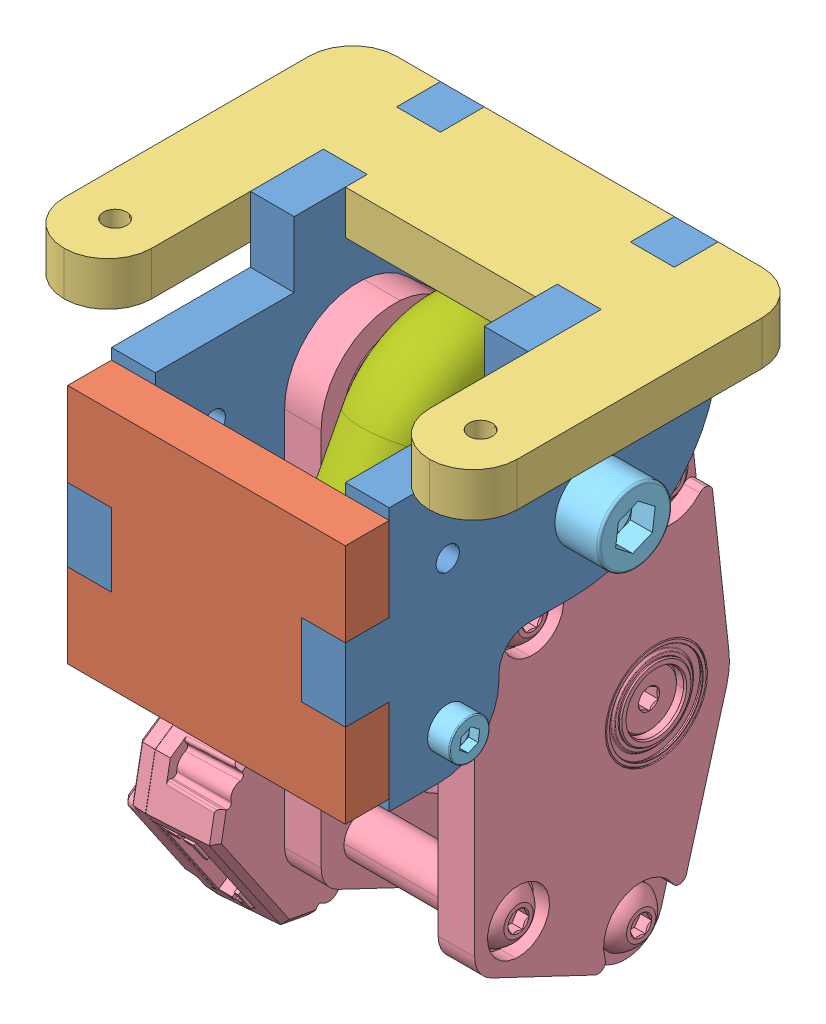
SolidWorks assembly Suporte odometria horizontal, configuration Valor predeterminado. Lengths in mm.
Overall size (62 88.3 69.49).
10 component instances, 7 part files, 21 mates.
Components (placement in the parent):
- M04.03.05.Lateral horizontal-1: M04.03.05.Lateral horizontal [Valor predeterminado] at (-73.7774 27.1656 115.2124) x (0 -1 0) z (-1 0 0) size (45 51 6)
- M04.03.06.Superior 6-1: M04.03.06.Superior 6 [Valor predeterminado] at (-60.7774 0.1656 115.2124) x (0 -1 0) z (0 0 1) size (33 38 6)
- M04.03.05.Lateral horizontal-2: M04.03.05.Lateral horizontal [Valor predeterminado] at (-41.7774 27.1656 115.2124) x (0 -1 0) z (-1 0 0) size (45 51 6)
- M04.03.07.Inferior 6-3: M04.03.07.Inferior 6 [Valor predeterminado] at (-60.7774 21.1656 79.7124) x (0 0 1) z (0 1 0) size (45.5 62 6)
- M04.03.08.Odometria-2: M04.03.08.Odometria [Valor predeterminado] at (-67.1156 -18.3079 73.5422) x (0 -0.996661 0.081653) z (1 0 0) size (73.49 51.17 39.86)
- socket head cap screw_iso-8: socket head cap screw_iso [ISO 4762 M6 x 10 - 10N] at (-35.7774 5.0156 87.5315) x (-1 0 0) z (0 0.924225 0.381849) size (16 10 10)
- torque nut 08_iso-1: torque nut 08_iso [ISO 10511-M3-N] at (-81.3274 11.0156 87.5315) x (0 0 1) z (-1 0 0) size (5.5 6.35 3.9)
- M04.03.09.Mola-1: M04.03.09.Mola [Valor predeterminado] at (-59.2813 4.7533 87.3426) x (0 -0.980257 0.197728) z (-1 0 0) size (38.69 42.17 12)
- socket head cap screw_iso-9: socket head cap screw_iso [ISO 4762 M3 x 40 - 40N] at (-38.7774 -11.8344 107.2124) x (-1 0 0) z (0 0.924225 0.381849) size (43 5.5 5.5)
- torque nut 08_iso-2: torque nut 08_iso [ISO 10511-M3-N] at (-81.3274 -11.8344 107.2124) x (0 0 1) z (-1 0 0) size (5.5 6.35 3.9)
Mates (geometry in assembly coordinates):
- Coincidente4: coincident anti-aligned: plane of M04.03.05.Lateral horizontal-1 through (-73.7774 27.1656 115.2124) normal (1 0 0); plane of M04.03.06.Superior 6-1 through (-73.7774 0.1656 121.2124) normal (-1 0 0)
- Coincidente5: coincident aligned: plane of M04.03.05.Lateral horizontal-1 through (-79.7774 27.1656 121.2124) normal (0 0 1); plane of M04.03.06.Superior 6-1 through (-60.7774 0.1656 121.2124) normal (0 0 1)
- Coincidente6: coincident anti-aligned: plane of M04.03.05.Lateral horizontal-1 through (-79.7774 5.1656 115.2124) normal (0 1 0); plane of M04.03.06.Superior 6-1 through (-60.7774 5.1656 121.2124) normal (0 -1 0)
- Coincidente9: coincident anti-aligned: plane of M04.03.06.Superior 6-1 through (-47.7774 0.1656 121.2124) normal (1 0 0); plane of M04.03.05.Lateral horizontal-2 through (-47.7774 27.1656 115.2124) normal (-1 0 0)
- Coincidente10: coincident aligned: plane of M04.03.06.Superior 6-1 through (-60.7774 0.1656 121.2124) normal (0 0 1); plane of M04.03.05.Lateral horizontal-2 through (-47.7774 27.1656 121.2124) normal (0 0 1)
- Coincidente11: coincident anti-aligned: plane of M04.03.06.Superior 6-1 through (-60.7774 5.1656 121.2124) normal (0 -1 0); plane of M04.03.05.Lateral horizontal-2 through (-47.7774 5.1656 115.2124) normal (0 1 0)
- Coincidente21: coincident anti-aligned: plane of M04.03.05.Lateral horizontal-1 through (-79.7774 21.1656 115.2124) normal (0 1 0); plane of M04.03.07.Inferior 6-3 through (-60.7774 21.1656 79.7124) normal (0 -1 0)
- Coincidente22: coincident anti-aligned: plane of M04.03.05.Lateral horizontal-1 through (-79.7774 27.1656 76.2124) normal (0 0 1); plane of M04.03.07.Inferior 6-3 through (-60.7774 27.1656 76.2124) normal (0 0 -1)
- Coincidente23: coincident anti-aligned: plane of M04.03.05.Lateral horizontal-1 through (-73.7774 27.1656 115.2124) normal (1 0 0); plane of M04.03.07.Inferior 6-3 through (-73.7774 27.1656 79.7124) normal (-1 0 0)
- Concêntrico9: concentric aligned: cylinder of M04.03.05.Lateral horizontal-1 through (-79.7774 5.0156 87.5315) axis (1 0 0) radius 3.15; cylinder of M04.03.08.Odometria-2 through (-52.7774 5.0156 87.5315) axis (1 0 0) radius 3
- Largura1: width anti-aligned: plane of M04.03.08.Odometria-2 through (-73.7774 -22.7279 76.4536) normal (-1 0 0); plane of M04.03.05.Lateral horizontal-1 through (-47.7774 -22.3605 80.9386) normal (1 0 0); plane of M04.03.08.Odometria-2 through (-73.7774 27.1656 115.2124) normal (1 0 0); plane of M04.03.05.Lateral horizontal-2 through (-47.7774 27.1656 115.2124) normal (-1 0 0)
- Paralelo1: parallel: plane of M04.03.06.Superior 6-1 through (-60.7774 0.1656 121.2124) normal (0 0 1); line of M04.03.08.Odometria-2 through (-68.7774 5.0156 97.5315) axis (0 -1 0)
- Concêntrico13: concentric aligned: cylinder of M04.03.05.Lateral horizontal-2 through (-47.7774 5.0156 87.5315) axis (1 0 0) radius 3.15; cylinder of socket head cap screw_iso-8 through (-4.0274 5.0156 87.5315) axis (1 0 0) radius 5
- Coincidente27: coincident anti-aligned: plane of M04.03.05.Lateral horizontal-2 through (-41.7774 27.1656 115.2124) normal (1 0 0); plane of socket head cap screw_iso-8 through (-41.7774 3.1064 92.1527) normal (-1 0 0)
- Coincidente28: coincident anti-aligned: plane of M04.03.05.Lateral horizontal-1 through (-79.7774 27.1656 115.2124) normal (-1 0 0); plane of torque nut 08_iso-1 through (-79.7774 14.1911 87.5315) normal (1 0 0)
- Concêntrico17: concentric anti-aligned: circle of Lateral 6-2; circle of Mola-1
- Concêntrico18: concentric anti-aligned: cylinder of M04.03.08.Odometria-2 through (-52.7774 -3.9331 70.5931) axis (-1 0 0) radius 2.975; cylinder of M04.03.09.Mola-1 through (-54.2813 -3.9331 70.5931) axis (1 0 0) radius 4
- Concêntrico19: concentric aligned: cylinder of M04.03.05.Lateral horizontal-2 through (-47.7774 -11.8344 107.2124) axis (1 0 0) radius 1.6; cylinder of socket head cap screw_iso-9 through (-7.0274 -11.8344 107.2124) axis (1 0 0) radius 2.75
- Coincidente29: coincident anti-aligned: plane of M04.03.05.Lateral horizontal-2 through (-41.7774 27.1656 115.2124) normal (1 0 0); plane of socket head cap screw_iso-9 through (-41.7774 -12.8844 109.754) normal (-1 0 0)
- Concêntrico20: concentric anti-aligned: cylinder of M04.03.05.Lateral horizontal-1 through (-79.7774 -11.8344 107.2124) axis (1 0 0) radius 1.6; cylinder of torque nut 08_iso-2 through (-100.3774 -11.8344 107.2124) axis (-1 0 0) radius 1.5
- Coincidente30: coincident anti-aligned: plane of M04.03.05.Lateral horizontal-1 through (-79.7774 27.1656 115.2124) normal (-1 0 0); plane of torque nut 08_iso-2 through (-79.7774 -8.6589 107.2124) normal (1 0 0)
